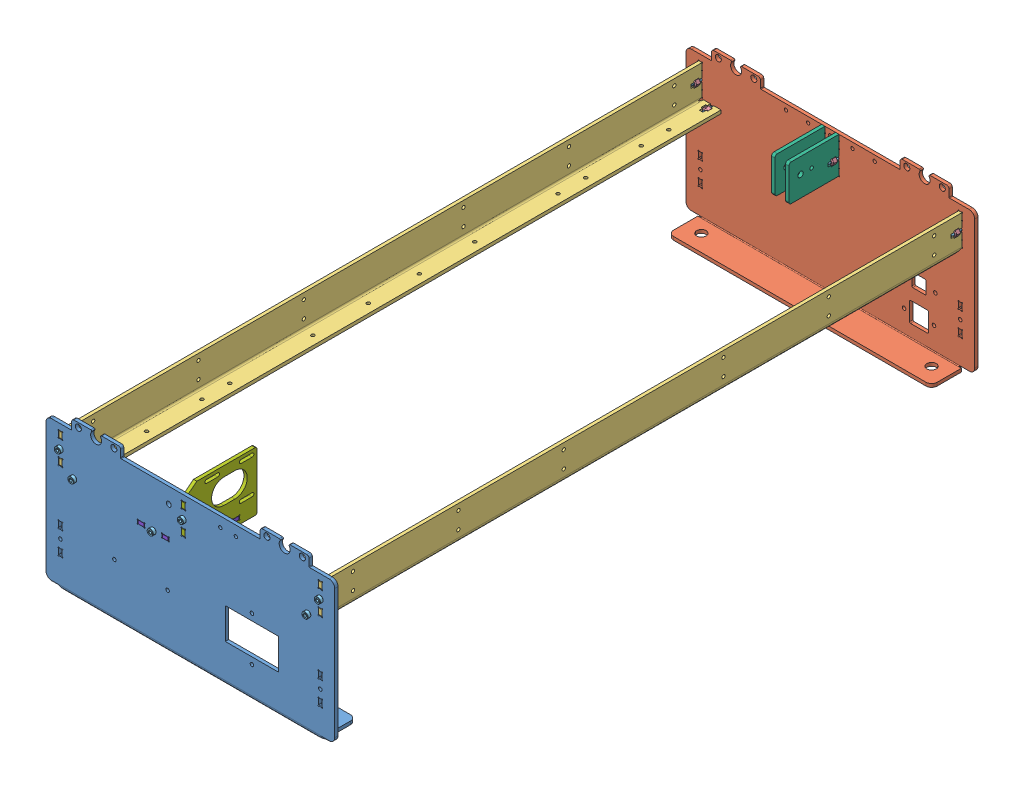
SolidWorks assembly ZorroChassisWithYAxis, configuration Default. Lengths in mm.
Overall size (260.35 138.91 586.93).
36 component instances, 8 part files, 29 mates.
Components (placement in the parent):
- ZorroChassis-1: ZorroChassis [Default] at (-1088.3709 427.4834 -288.3354) size (260.35 138.87 586.29)
  - ChassisBackPlate-1: ChassisBackPlate [Default] at (-181.486 448.7837 -85.9696) size (260.35 138.87 30.49)
  - ChassisFrontPlate-1: ChassisFrontPlate [Default] at (356.5344 448.7837 -659.9695) x (-1 0 0) z (0 0 -1) size (260.35 138.87 30.49)
  - ChassisSidePlate-1: ChassisSidePlate [Default] at (-163.7656 19.1363 -785.5189) x (-1 0 0) z (0 0 -1) size (20.15 31.34 580)
  - ChassisSidePlate-2: ChassisSidePlate [Default] at (67.5844 19.1363 39.5799) size (20.15 31.34 580)
  - 90576A102_ZINC-PLATED CLASS 8 STL NYLON-INSERT LOCKNUT-1: 90576A102_ZINC-PLATED CLASS 8 STL NYLON-INSERT LOCKNUT [90576A102] at (69.0844 727.9199 -657.1695) x (0 -1 0) z (-1 0 0) size (5.5 4.1 6.35)
  - 91292A114_TYPE 18-8 SS SOCKET HEAD CAP SCREW-1: 91292A114_TYPE 18-8 SS SOCKET HEAD CAP SCREW [91292A114] at (69.0844 727.9199 -650.9695) x (-0.962816 0.270159 0) z (0 0 1) size (5.5 5.5 15.58)
  - 91292A114_TYPE 18-8 SS SOCKET HEAD CAP SCREW-2: 91292A114_TYPE 18-8 SS SOCKET HEAD CAP SCREW [91292A114] at (-165.2656 727.9199 -650.9695) size (5.5 5.5 15.58)
  - 90576A102_ZINC-PLATED CLASS 8 STL NYLON-INSERT LOCKNUT-2: 90576A102_ZINC-PLATED CLASS 8 STL NYLON-INSERT LOCKNUT [90576A102] at (-165.2656 727.9199 -657.1695) x (-0.866025 0.5 0) z (0.5 0.866025 0) size (5.5 4.1 6.35)
  - 91292A114_TYPE 18-8 SS SOCKET HEAD CAP SCREW-3: 91292A114_TYPE 18-8 SS SOCKET HEAD CAP SCREW [91292A114] at (69.0844 727.9199 -94.9696) x (-1 0 0) z (0 0 -1) size (5.5 5.5 15.58)
  - 91292A114_TYPE 18-8 SS SOCKET HEAD CAP SCREW-4: 91292A114_TYPE 18-8 SS SOCKET HEAD CAP SCREW [91292A114] at (-165.2656 727.9199 -94.9696) x (-1 0 0) z (0 0 -1) size (5.5 5.5 15.58)
  - 90576A102_ZINC-PLATED CLASS 8 STL NYLON-INSERT LOCKNUT-3: 90576A102_ZINC-PLATED CLASS 8 STL NYLON-INSERT LOCKNUT [90576A102] at (69.0844 727.9199 -88.7696) x (0 -1 0) z (1 0 0) size (5.5 4.1 6.35)
  - 90576A102_ZINC-PLATED CLASS 8 STL NYLON-INSERT LOCKNUT-4: 90576A102_ZINC-PLATED CLASS 8 STL NYLON-INSERT LOCKNUT [90576A102] at (-165.2656 727.9199 -88.7696) x (0.866025 -0.5 0) z (0.5 0.866025 0) size (5.5 4.1 6.35)
  - 90576A102_ZINC-PLATED CLASS 8 STL NYLON-INSERT LOCKNUT-5: 90576A102_ZINC-PLATED CLASS 8 STL NYLON-INSERT LOCKNUT [90576A102] at (58.4344 710.6698 -657.1695) x (-0.5 -0.866025 0) z (-0.866025 0.5 0) size (5.5 4.1 6.35)
  - 90576A102_ZINC-PLATED CLASS 8 STL NYLON-INSERT LOCKNUT-7: 90576A102_ZINC-PLATED CLASS 8 STL NYLON-INSERT LOCKNUT [90576A102] at (-154.6157 710.6698 -657.1695) x (0.5 -0.866025 0) z (-0.866025 -0.5 0) size (5.5 4.1 6.35)
  - 90576A102_ZINC-PLATED CLASS 8 STL NYLON-INSERT LOCKNUT-9: 90576A102_ZINC-PLATED CLASS 8 STL NYLON-INSERT LOCKNUT [90576A102] at (58.0015 710.6698 -88.7696) x (-0.5 0.866025 0) z (-0.866025 -0.5 0) size (5.5 4.1 6.35)
  - 90576A102_ZINC-PLATED CLASS 8 STL NYLON-INSERT LOCKNUT-10: 90576A102_ZINC-PLATED CLASS 8 STL NYLON-INSERT LOCKNUT [90576A102] at (-153.0485 710.6698 -88.7696) x (0.5 0.866025 0) z (-0.866025 0.5 0) size (5.5 4.1 6.35)
  - 91292A114_TYPE 18-8 SS SOCKET HEAD CAP SCREW-5: 91292A114_TYPE 18-8 SS SOCKET HEAD CAP SCREW [91292A114] at (58.4344 710.6698 -650.9695) size (5.5 5.5 15.58)
  - 91292A114_TYPE 18-8 SS SOCKET HEAD CAP SCREW-6: 91292A114_TYPE 18-8 SS SOCKET HEAD CAP SCREW [91292A114] at (-154.6157 710.6698 -650.9695) size (5.5 5.5 15.58)
  - 91292A114_TYPE 18-8 SS SOCKET HEAD CAP SCREW-7: 91292A114_TYPE 18-8 SS SOCKET HEAD CAP SCREW [91292A114] at (58.0015 710.6698 -94.9696) x (1 0 0) z (0 0 -1) size (5.5 5.5 15.58)
  - 91292A114_TYPE 18-8 SS SOCKET HEAD CAP SCREW-8: 91292A114_TYPE 18-8 SS SOCKET HEAD CAP SCREW [91292A114] at (-153.0485 710.6698 -94.9696) x (1 0 0) z (0 0 -1) size (5.5 5.5 15.58)
- Y-axis-bearing-side-1: Y-axis-bearing-side [Default] at (-1141.2615 983.7613 -1097.325) x (0 0 1) z (-1 0 0) size (48.17 32.6 3)
- Y-axis-bearing-side-2: Y-axis-bearing-side [Default] at (-1128.6615 983.7613 -1097.325) x (0 0 1) z (-1 0 0) size (48.17 32.6 3)
- Y-Motor-mount-1: Y-Motor-mount [Default] at (-1214.7316 806.962 -603.9804) x (-0.00302 0.998888 -0.047045) z (0.999694 0.00186 -0.024683) size (56.01 67.48 56.34)
  - Y-Axis-Motor-Mount-front-1: Y-Axis-Motor-Mount-front [Default] at (38.5196 15.1092 70.2367) x (0.998888 0.047105 0.00186) z (-0.00302 0.024568 0.999694) size (53 65 3)
  - Y-Axis-Motor-Mount-bottom-1: Y-Axis-Motor-Mount-bottom [Default] at (323.8552 80.0232 292.6918) x (-0.047045 0.998588 -0.024683) z (-0.998888 -0.047105 -0.00186) size (58.68 52.33 3)
  - 90576A102_ZINC-PLATED CLASS 8 STL NYLON-INSERT LOCKNUT-1: 90576A102_ZINC-PLATED CLASS 8 STL NYLON-INSERT LOCKNUT [90576A102] at (316.4422 214.4296 63.3769) x (0.84154 0.540088 -0.010731) z (-0.540186 0.84125 -0.022306) size (5.5 4.1 6.35)
  - 91292A114_TYPE 18-8 SS SOCKET HEAD CAP SCREW-1: 91292A114_TYPE 18-8 SS SOCKET HEAD CAP SCREW [91292A114] at (316.4609 214.2773 57.1788) x (-0.643982 0.76476 -0.02074) z (0.00302 -0.024568 -0.999694) size (5.5 5.5 15.58)
- 90576A102_ZINC-PLATED CLASS 8 STL NYLON-INSERT LOCKNUT-1: 90576A102_ZINC-PLATED CLASS 8 STL NYLON-INSERT LOCKNUT [90576A102] at (-1142.7615 1155.7909 -945.5048) x (0.866025 -0.5 0) z (-0.5 -0.866025 0) size (5.5 4.1 6.35)
- 90576A102_ZINC-PLATED CLASS 8 STL NYLON-INSERT LOCKNUT-2: 90576A102_ZINC-PLATED CLASS 8 STL NYLON-INSERT LOCKNUT [90576A102] at (-1130.1615 1155.7909 -945.5048) x (0.866025 0.5 0) z (0.5 -0.866025 0) size (5.5 4.1 6.35)
- 90576A102_ZINC-PLATED CLASS 8 STL NYLON-INSERT LOCKNUT-3: 90576A102_ZINC-PLATED CLASS 8 STL NYLON-INSERT LOCKNUT [90576A102] at (-1169.9137 1133.2709 -377.0832) x (0.5 -0.866025 0) z (0.866025 0.5 0) size (5.5 4.1 6.35)
- 90576A102_ZINC-PLATED CLASS 8 STL NYLON-INSERT LOCKNUT-4: 90576A102_ZINC-PLATED CLASS 8 STL NYLON-INSERT LOCKNUT [90576A102] at (-1142.7615 1155.7909 -377.1049) x (0 1 0) z (-1 0 0) size (5.5 4.1 6.35)
- 91292A114_TYPE 18-8 SS SOCKET HEAD CAP SCREW-1: 91292A114_TYPE 18-8 SS SOCKET HEAD CAP SCREW [91292A114] at (-1142.7615 1155.7909 -939.3049) size (5.5 5.5 15.58)
- 91292A114_TYPE 18-8 SS SOCKET HEAD CAP SCREW-2: 91292A114_TYPE 18-8 SS SOCKET HEAD CAP SCREW [91292A114] at (-1130.1615 1155.7909 -939.3049) size (5.5 5.5 15.58)
- 91292A114_TYPE 18-8 SS SOCKET HEAD CAP SCREW-3: 91292A114_TYPE 18-8 SS SOCKET HEAD CAP SCREW [91292A114] at (-1169.9137 1133.2709 -383.305) x (1 0 0) z (0 0 -1) size (5.5 5.5 15.58)
- 91292A114_TYPE 18-8 SS SOCKET HEAD CAP SCREW-4: 91292A114_TYPE 18-8 SS SOCKET HEAD CAP SCREW [91292A114] at (-1142.7615 1155.7909 -383.305) x (1 0 0) z (0 0 -1) size (5.5 5.5 15.58)
Mates (geometry in assembly coordinates):
- Width1: width anti-aligned: plane of Y-axis-bearing-side-2 through (-1128.6615 1142.6909 -950.8049) normal (1 0 0); plane of Y-axis-bearing-side-2 through (-1131.6615 1142.6909 -950.8049) normal (-1 0 0); plane of ZorroChassis-1/ChassisFrontPlate-1 through (-1128.5116 1168.6249 -951.3049) normal (-1 0 0); plane of ZorroChassis-1/ChassisFrontPlate-1 through (-1131.8115 1164.1569 -951.3049) normal (1 0 0)
- Width2: width anti-aligned: plane of Y-axis-bearing-side-2 through (-1131.6615 1169.3909 -949.1708) normal (0 1 0); plane of Y-axis-bearing-side-2 through (-1131.6615 1163.3909 -950.8049) normal (0 -1 0); plane of ZorroChassis-1/ChassisFrontPlate-1 through (-1130.9454 1169.4909 -951.3049) normal (0 -1 0); plane of ZorroChassis-1/ChassisFrontPlate-1 through (-1129.3776 1163.2909 -951.3049) normal (0 1 0)
- Coincident10: coincident aligned: plane of ZorroChassis-1/ChassisFrontPlate-1 through (-1261.6365 1169.7947 -951.3049) normal (0 0 -1); plane of Y-axis-bearing-side-2 through (-1131.6615 1168.8909 -951.3049) normal (0 0 -1)
- Width3: width anti-aligned: plane of Y-axis-bearing-side-1 through (-1141.2615 1142.6909 -950.8049) normal (1 0 0); plane of Y-axis-bearing-side-1 through (-1144.2615 1142.6909 -950.8049) normal (-1 0 0); plane of ZorroChassis-1/ChassisFrontPlate-1 through (-1141.1116 1168.6249 -951.3049) normal (-1 0 0); plane of ZorroChassis-1/ChassisFrontPlate-1 through (-1144.4115 1164.1569 -951.3049) normal (1 0 0)
- Width4: width anti-aligned: plane of Y-axis-bearing-side-1 through (-1144.2615 1169.3909 -949.1708) normal (0 1 0); plane of Y-axis-bearing-side-1 through (-1144.2615 1163.3909 -950.8049) normal (0 -1 0); plane of ZorroChassis-1/ChassisFrontPlate-1 through (-1143.5454 1169.4909 -951.3049) normal (0 -1 0); plane of ZorroChassis-1/ChassisFrontPlate-1 through (-1141.9776 1163.2909 -951.3049) normal (0 1 0)
- Coincident11: coincident aligned: plane of ZorroChassis-1/ChassisFrontPlate-1 through (-1261.6365 1169.7947 -951.3049) normal (0 0 -1); plane of Y-axis-bearing-side-1 through (-1144.2615 1168.8909 -951.3049) normal (0 0 -1)
- Width5: width anti-aligned: plane of ZorroChassis-1/ChassisBackPlate-1 through (-1141.1115 1164.1569 -371.305) normal (-1 0 0); plane of ZorroChassis-1/ChassisBackPlate-1 through (-1144.4115 1168.6249 -371.305) normal (1 0 0); plane of Y-Motor-mount-1/Y-Axis-Motor-Mount-front-1 through (-1141.2615 1142.1909 -374.3049) normal (1 0 0); plane of Y-Motor-mount-1/Y-Axis-Motor-Mount-front-1 through (-1144.2615 1142.1909 -374.3049) normal (-1 0 0)
- Width6: width anti-aligned: plane of Y-Motor-mount-1/Y-Axis-Motor-Mount-front-1 through (-1141.2615 1169.3909 -373.4389) normal (0 1 0); plane of Y-Motor-mount-1/Y-Axis-Motor-Mount-front-1 through (-1141.2615 1163.3909 -371.8049) normal (0 -1 0); plane of ZorroChassis-1/ChassisBackPlate-1 through (-1141.9776 1169.4909 -371.305) normal (0 -1 0); plane of ZorroChassis-1/ChassisBackPlate-1 through (-1143.5454 1163.2909 -371.305) normal (0 1 0)
- Coincident12: coincident anti-aligned: plane of ZorroChassis-1/ChassisBackPlate-1 through (-1011.2865 1169.7947 -374.305) normal (0 0 -1); plane of Y-Motor-mount-1/Y-Axis-Motor-Mount-front-1 through (-1141.2615 1162.5249 -374.305) normal (0 0 1)
- Coincident13: coincident anti-aligned: plane of Y-Motor-mount-1/Y-Axis-Motor-Mount-front-1 through (-1141.2615 1152.9159 -377.1049) normal (0 0 -1); plane of 90576A102_ZINC-PLATED CLASS 8 STL NYLON-INSERT LOCKNUT-4 through (-1141.1738 1158.5409 -377.1049) normal (0 0 1)
- Coincident14: coincident anti-aligned: plane of Y-Motor-mount-1/Y-Axis-Motor-Mount-bottom-1 through (-1168.2719 1131.7709 -377.0832) normal (0 0 -1); plane of 90576A102_ZINC-PLATED CLASS 8 STL NYLON-INSERT LOCKNUT-3 through (-1169.9137 1130.0955 -377.0832) normal (0 0 1)
- Concentric1: concentric anti-aligned: circle of 90576A102_ZINC-PLATED CLASS 8 STL NYLON-INSERT LOCKNUT-3; cylinder of ZorroChassis-1/ChassisBackPlate-1 through (-1169.9137 1133.2709 -371.305) axis (0 0 -1) radius 1.6
- Concentric2: concentric anti-aligned: cylinder of ZorroChassis-1/ChassisBackPlate-1 through (-1142.7615 1155.7909 -371.305) axis (0 0 -1) radius 1.6; circle of 90576A102_ZINC-PLATED CLASS 8 STL NYLON-INSERT LOCKNUT-4
- Parallel1: parallel anti-aligned: plane of Y-Motor-mount-1/Y-Axis-Motor-Mount-bottom-1 through (-1166.9637 1131.7709 -377.0832) normal (-1 0 0); plane of 90576A102_ZINC-PLATED CLASS 8 STL NYLON-INSERT LOCKNUT-3 through (-1167.1637 1134.8586 -381.0832) normal (1 0 0)
- Parallel2: parallel anti-aligned: plane of Y-Motor-mount-1/Y-Axis-Motor-Mount-front-1 through (-1141.2615 1152.9159 -381.3049) normal (0 1 0); plane of 90576A102_ZINC-PLATED CLASS 8 STL NYLON-INSERT LOCKNUT-4 through (-1141.1738 1153.0409 -381.1049) normal (0 -1 0)
- Coincident15: coincident anti-aligned: plane of ZorroChassis-1/ChassisBackPlate-1 through (-1011.2865 1169.7947 -371.305) normal (0 0 1); plane of 91292A114_TYPE 18-8 SS SOCKET HEAD CAP SCREW-4 through (-1142.7615 1155.7909 -371.305) normal (0 0 -1)
- Concentric3: concentric aligned: cylinder of ZorroChassis-1/ChassisBackPlate-1 through (-1142.7615 1155.7909 -371.305) axis (0 0 -1) radius 1.6; cylinder of 91292A114_TYPE 18-8 SS SOCKET HEAD CAP SCREW-4 through (-1142.7615 1155.7909 -368.305) axis (0 0 -1) radius 2.75
- Coincident16: coincident anti-aligned: plane of ZorroChassis-1/ChassisBackPlate-1 through (-1011.2865 1169.7947 -371.305) normal (0 0 1); plane of 91292A114_TYPE 18-8 SS SOCKET HEAD CAP SCREW-3 through (-1169.9137 1133.2709 -371.305) normal (0 0 -1)
- Concentric4: concentric aligned: cylinder of ZorroChassis-1/ChassisBackPlate-1 through (-1169.9137 1133.2709 -371.305) axis (0 0 -1) radius 1.6; cylinder of 91292A114_TYPE 18-8 SS SOCKET HEAD CAP SCREW-3 through (-1169.9137 1133.2709 -368.305) axis (0 0 -1) radius 2.75
- Coincident17: coincident anti-aligned: plane of Y-axis-bearing-side-1 through (-1144.2615 1152.9159 -945.5048) normal (0 0 1); plane of 90576A102_ZINC-PLATED CLASS 8 STL NYLON-INSERT LOCKNUT-1 through (-1139.5861 1155.7909 -945.5048) normal (0 0 -1)
- Concentric5: concentric anti-aligned: cylinder of ZorroChassis-1/ChassisFrontPlate-1 through (-1142.7615 1155.7909 -951.3049) axis (0 0 1) radius 1.6; circle of 90576A102_ZINC-PLATED CLASS 8 STL NYLON-INSERT LOCKNUT-1
- Parallel3: parallel aligned: plane of Y-axis-bearing-side-1 through (-1144.2615 1152.9159 -941.3048) normal (0 1 0); plane of 90576A102_ZINC-PLATED CLASS 8 STL NYLON-INSERT LOCKNUT-1 through (-1141.1738 1158.5409 -941.5048) normal (0 1 0)
- Coincident18: coincident anti-aligned: plane of ZorroChassis-1/ChassisFrontPlate-1 through (-1261.6365 1169.7947 -951.3049) normal (0 0 -1); plane of 91292A114_TYPE 18-8 SS SOCKET HEAD CAP SCREW-1 through (-1142.7615 1155.7909 -951.3049) normal (0 0 1)
- Concentric6: concentric aligned: cylinder of ZorroChassis-1/ChassisFrontPlate-1 through (-1142.7615 1155.7909 -951.3049) axis (0 0 1) radius 1.6; cylinder of 91292A114_TYPE 18-8 SS SOCKET HEAD CAP SCREW-1 through (-1142.7615 1155.7909 -954.3049) axis (0 0 1) radius 2.75
- Coincident19: coincident anti-aligned: plane of Y-axis-bearing-side-2 through (-1131.6615 1152.9159 -945.5048) normal (0 0 1); plane of 90576A102_ZINC-PLATED CLASS 8 STL NYLON-INSERT LOCKNUT-2 through (-1127.4115 1157.3786 -945.5048) normal (0 0 -1)
- Concentric8: concentric anti-aligned: cylinder of ZorroChassis-1/ChassisFrontPlate-1 through (-1130.1615 1155.7909 -951.3049) axis (0 0 1) radius 1.6; circle of 90576A102_ZINC-PLATED CLASS 8 STL NYLON-INSERT LOCKNUT-2
- Coincident20: coincident: plane of ZorroChassis-1/ChassisFrontPlate-1 through (-1261.6365 1169.7947 -951.3049) normal (0 0 -1); plane of 91292A114_TYPE 18-8 SS SOCKET HEAD CAP SCREW-2 through (-1130.1615 1155.7909 -951.3049) normal (0 0 1)
- Concentric9: concentric aligned: cylinder of ZorroChassis-1/ChassisFrontPlate-1 through (-1130.1615 1155.7909 -951.3049) axis (0 0 1) radius 1.6; cylinder of 91292A114_TYPE 18-8 SS SOCKET HEAD CAP SCREW-2 through (-1130.1615 1155.7909 -954.3049) axis (0 0 1) radius 2.75
- Parallel4: parallel aligned: plane of Y-axis-bearing-side-2 through (-1131.6615 1152.9159 -941.3048) normal (0 1 0); plane of 90576A102_ZINC-PLATED CLASS 8 STL NYLON-INSERT LOCKNUT-2 through (-1128.5738 1158.5409 -941.5048) normal (0 1 0)
